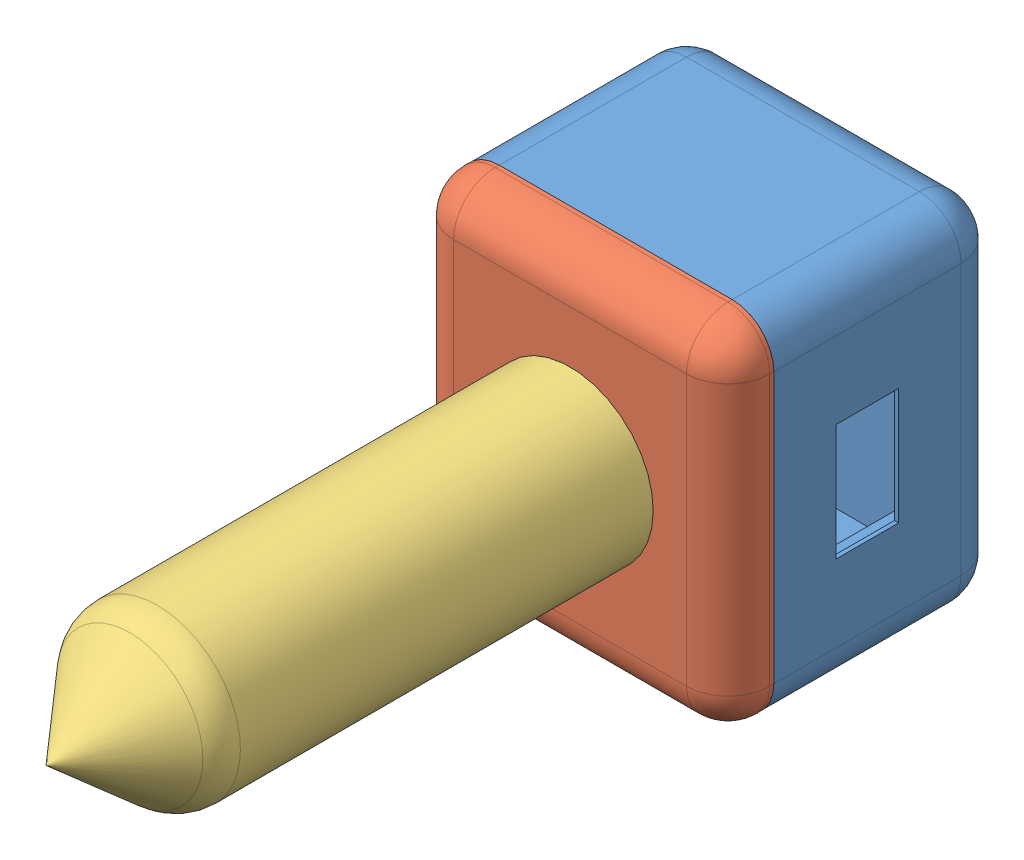
SolidWorks assembly Ensamblaje2, configuration Predeterminado. Lengths in mm.
Overall size (76 85 192).
3 component instances, 3 part files, 4 mates.
Components (placement in the parent):
- Pieza1-1: Pieza1 [Predeterminado] at (-5.0522 1.4099 57.5) size (76 85 55)
- Pieza2-1: Pieza2 [Predeterminado] at (-5.0522 1.4099 112.5) size (76 85 11)
- Pieza3-1: Pieza3 [Predeterminado] at (-5.0522 1.4099 126.4961) x (0.791279 -0.611455 0) z (-0.611455 -0.791279 0) size (40 128 40)
Mates (geometry in assembly coordinates):
- Coincidente1: coincident anti-aligned: plane of Pieza1-1 through (-5.0522 1.4099 112.5) normal (0 0 1); plane of Pieza2-1 through (-5.0522 1.4099 112.5) normal (0 0 -1)
- Coincidente2: coincident aligned: line of Pieza1-1 through (32.9478 -31.0901 112.5) axis (0 1 0); line of Pieza2-1 through (32.9478 -31.0901 112.5) axis (0 1 0)
- Coincidente3: coincident aligned: line of Pieza1-1 through (-33.0522 -41.0901 112.5) axis (1 0 0); line of Pieza2-1 through (-33.0522 -41.0901 112.5) axis (1 0 0)
- Concéntrica1: concentric aligned: circle of Pieza2-1; circle of Pieza3-1
